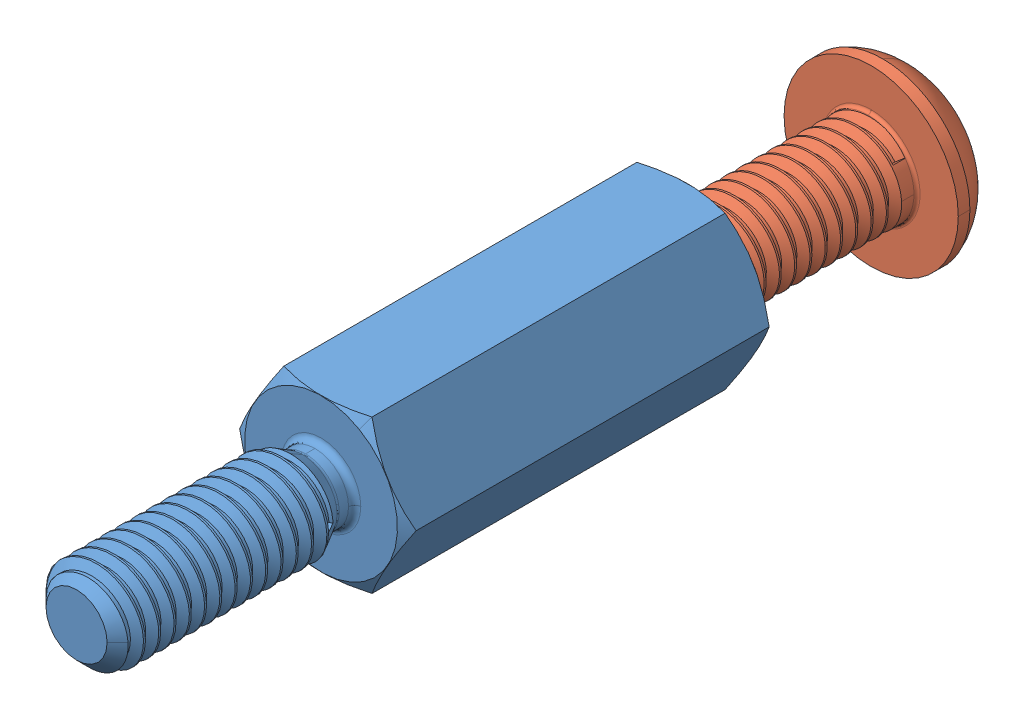
SolidWorks assembly Assem26, configuration Default. Lengths in mm.
Overall size (5.77 5.7 27.65).
2 component instances, 2 part files, 0 mates.
Components (placement in the parent):
- brass_M3_12mm_threaded-1: brass_M3_12mm_threaded [Predeterminado] at origin size (5.77 5 20.19)
- brass_button-head_screw_m3x8_threaded-1: brass_button-head_screw_m3x8_threaded [Predeterminado] at (0 0 -18) x (-1 0 0) z (0 0 -1) size (5.7 5.7 9.77)
